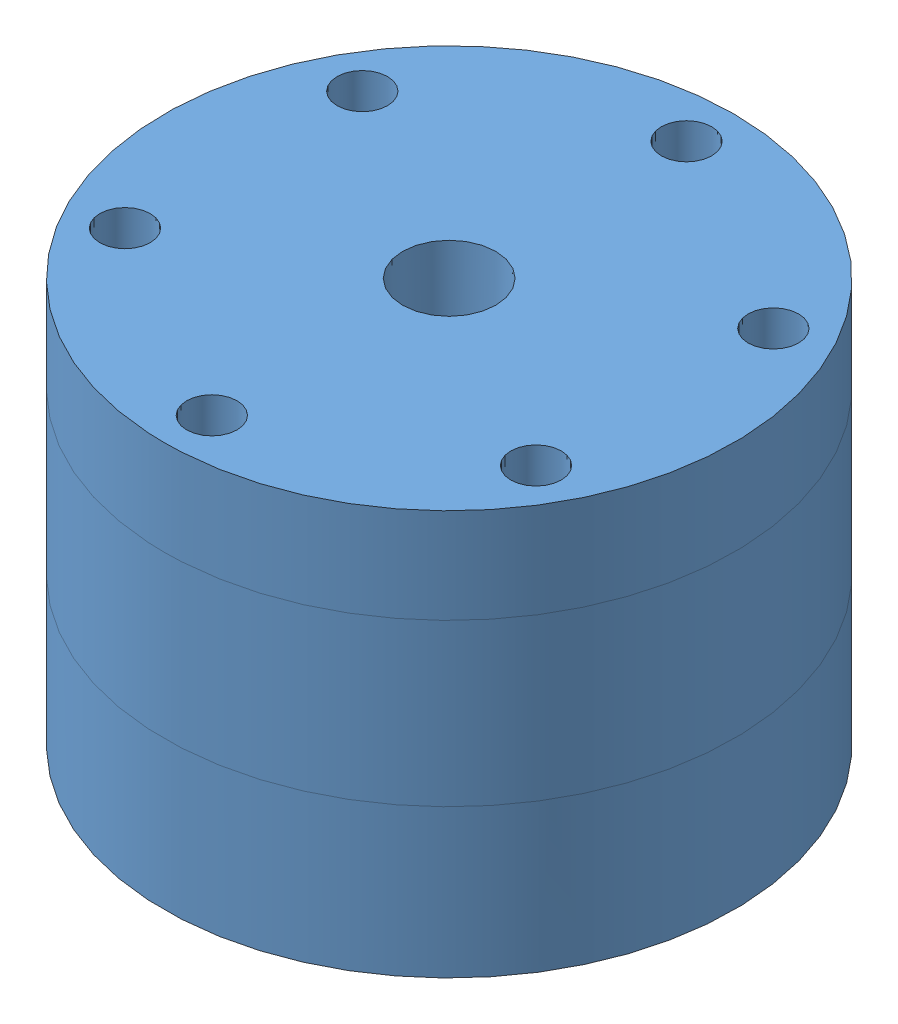
SolidWorks assembly swirl tester, configuration Default. Lengths in mm.
Overall size (76.2 54.13 76.2).
2 component instances, 2 part files, 3 mates.
Components (placement in the parent):
- swirl tester manifold 1-1: swirl tester manifold 1 [Default] at origin size (76.2 54.13 76.2)
- test swirler 1-1: test swirler 1 [Default] at (0 -15.2383 0) size (25.4 23.01 25.4)
Mates (geometry in assembly coordinates):
- Coincident1: coordinate: point of swirl tester manifold 1-1
- Concentric1: concentric anti-aligned: cylinder of swirl tester manifold 1-1 through (0 -86.75 0) axis (0 -1 0) radius 6.35; cylinder of test swirler 1-1 through (0 -16.8258 0) axis (0 1 0) radius 6.35
- Coincident2: coincident anti-aligned: plane of swirl tester manifold 1-1 through (-6.35 -35.0774 0) normal (0 1 0); plane of test swirler 1-1 through (-6.35 -35.0774 0) normal (0 -1 0)
